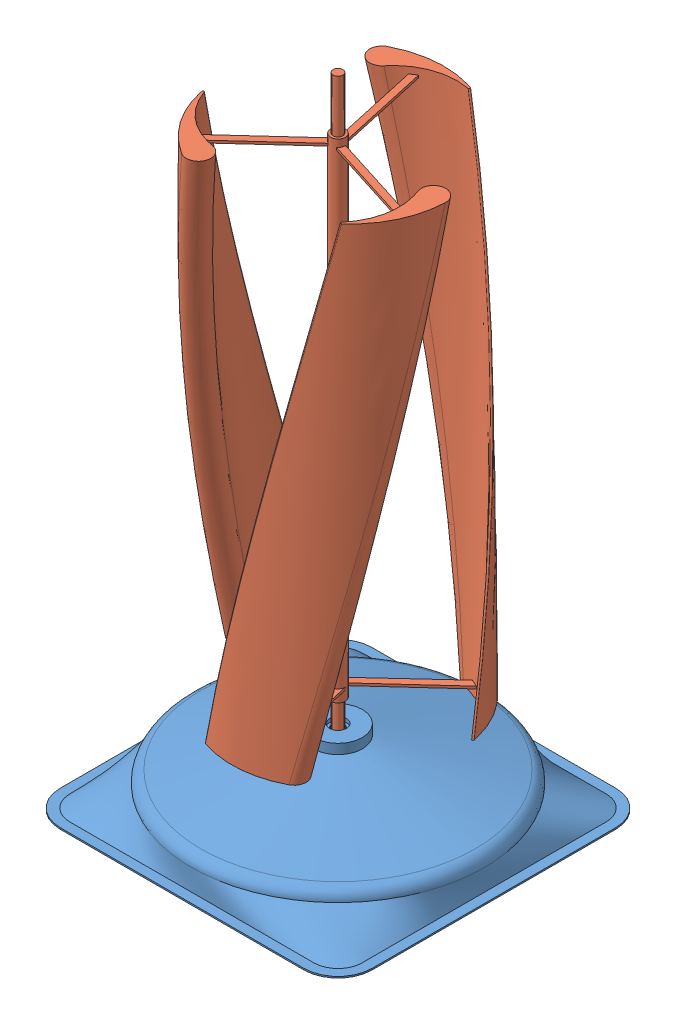
SolidWorks assembly Assem1, configuration Default. Lengths in mm.
Overall size (640 1310 640).
2 component instances, 2 part files, 2 mates.
Components (placement in the parent):
- waaier onderkant-1: waaier onderkant [Default] at (-11.9047 -91.6542 18.6156) size (640 153 640)
- waaier middelstuk-1: waaier middelstuk [Default] at (-2.3821 -94.6542 21.6685) x (-0.952261 0 -0.305284) z (0.305284 0 -0.952261) size (478.85 1310 467.67)
Mates (geometry in assembly coordinates):
- Concentric1: concentric: cylinder of waaier onderkant-1 through (-11.9047 -94.6542 18.6156) axis (0 -1 0) radius 12.5; cylinder of waaier middelstuk-1 through (-11.9047 -94.6542 18.6156) axis (0 -1 0) radius 10
- Coincident1: coincident: plane of waaier onderkant-1 through (-11.9047 -94.6542 18.6156) normal (0 -1 0); plane of waaier middelstuk-1 through (-2.3821 -94.6542 21.6685) normal (0 -1 0)
